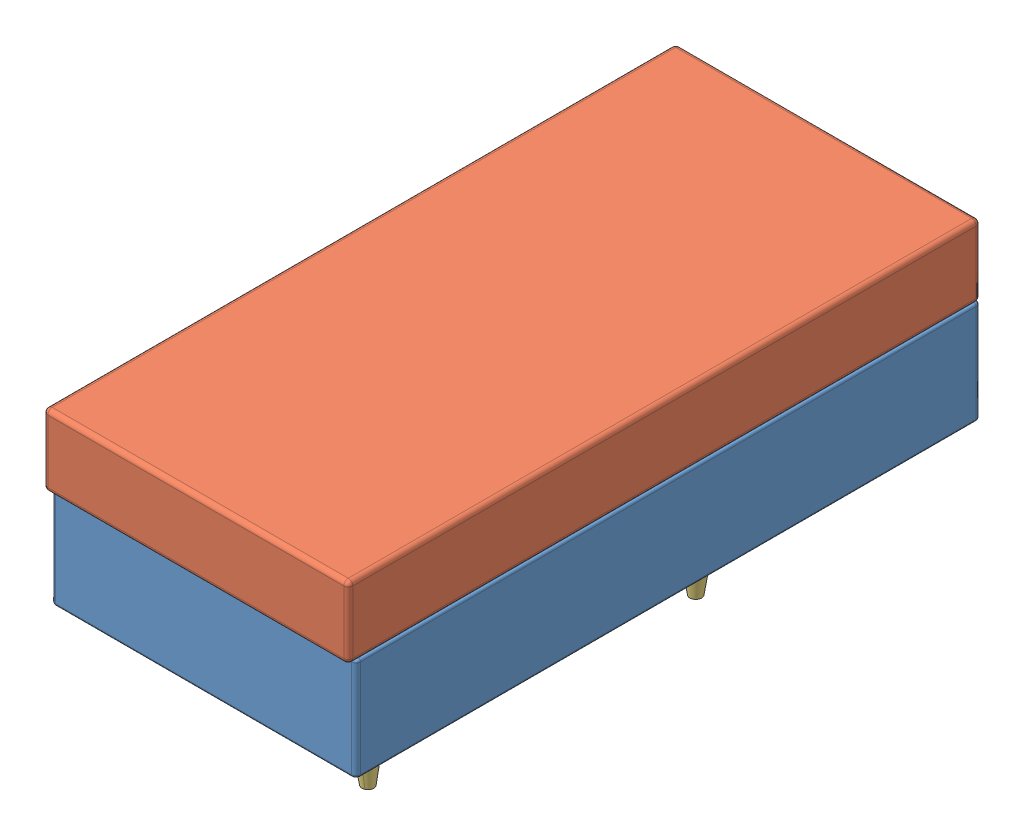
SolidWorks assembly Aufklappbox, configuration Standard. Lengths in mm.
Overall size (680.19 440.78 1410.02).
4 component instances, 3 part files, 12 mates.
Components (placement in the parent):
- Aufbewahrungsbox-1: Aufbewahrungsbox [Standard] at (370 0 -1427.3141) x (-1 0 0) z (0 1 0) size (680.04 1392.73 228.2)
- Aufbewahrungsmatratze-1: Aufbewahrungsmatratze [Standard] at (370 0 -1410) x (-1 0 0) z (0 1 0) size (680 1410 160)
- Standfuss-1: Standfuss [Standard] at (-1196.5877 1.7018 -1670.6769) x (-0.601985 0 0.798507) z (0.000936 0.999999 0.000706) size (43.37 42.87 53.74)
- Standfuss-2: Standfuss [Standard] at (1284.7339 1.7018 -690.2598) x (-0.418517 0 -0.908209) z (-0.001065 0.999999 0.000491) size (43.37 42.87 53.74)
Mates (geometry in assembly coordinates):
- Deckungsgleich1: coincident anti-aligned: plane of Aufbewahrungsbox-1 through (-1360.2131 -160 -1410) normal (0 1 0); plane of Aufbewahrungsmatratze-1 through (-1360.2131 -160 -1410) normal (0 -1 0)
- Deckungsgleich2: coincident aligned: plane of Aufbewahrungsbox-1 through (-1360.2131 -160 -1410) normal (0 0 -1); plane of Aufbewahrungsmatratze-1 through (-1360.2131 0 -1410) normal (0 0 -1)
- Deckungsgleich3: coincident aligned: plane of Aufbewahrungsbox-1 through (-1360.2131 -160 -17.3141) normal (-1 0 0); plane of Aufbewahrungsmatratze-1 through (-1360.2131 0 0) normal (-1 0 0)
- Deckungsgleich4: coincident: plane of Aufbewahrungsbox-1 through (-680 -388.1981 -1410) normal (0 -1 0); plane of Standfuss-2 through (-609.8375 -388.1981 -61.937) normal (0 1 0)
- Deckungsgleich5: coincident: plane of Aufbewahrungsbox-1 through (-680 -388.1981 -1410) normal (0 -1 0); plane of Standfuss-1 through (-659.8597 -388.1981 -845.245) normal (0 1 0)
- Abstand4: distance = 600 mm: line of Aufbewahrungsbox-1 through (-670 -388.1981 -1405) axis (1 0 0); line of Standfuss-1 through (-30.828 -440.0005 -805.5786) axis (0.01592 0.999801 0.012002)
- Abstand5: distance = 50 mm: line of Standfuss-2 through (-29.0659 -440.0005 -72.7482) axis (-0.018107 0.999801 0.008344); line of Aufbewahrungsbox-1 through (-10 -388.1981 -22.3141) axis (-1 0 0)
- Abstand6: distance = 25 mm: line of Standfuss-2 through (-29.0659 -440.0005 -72.7482) axis (-0.018107 0.999801 0.008344); line of Aufbewahrungsbox-1 through (-5 -388.1981 -1400) axis (0 0 1)
- Abstand7: distance = 25 mm: line of Standfuss-1 through (-30.828 -440.0005 -805.5786) axis (0.01592 0.999801 0.012002); line of Aufbewahrungsbox-1 through (-5 -388.1981 -1400) axis (0 0 1)
- Deckungsgleich6: coincident aligned: plane of Aufbewahrungsmatratze-1 through (-680 0 -1410) normal (0 1 0); plane of assembly
- Deckungsgleich7: coincident aligned: plane of Aufbewahrungsmatratze-1 through (0 0 0) normal (0 0 1); plane of assembly
- Deckungsgleich8: coincident aligned: plane of Aufbewahrungsbox-1 through (0 -160 -1410) normal (1 0 0); plane of assembly
